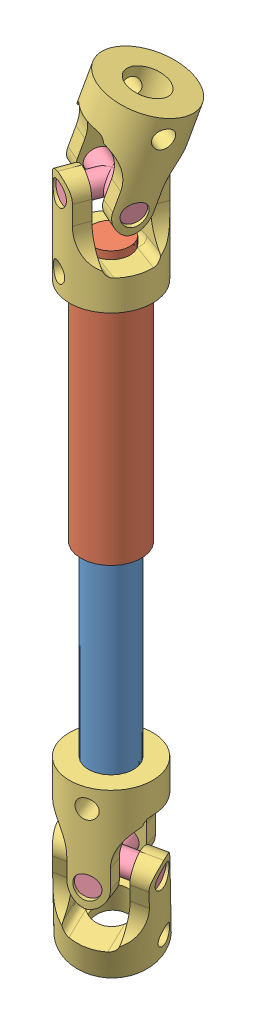
SolidWorks assembly Ujoin axle, configuration Default. Lengths in mm.
Overall size (22.93 105.93 22.35).
10 component instances, 4 part files, 5 mates.
Components (placement in the parent):
- eixo ujoint inner-1: eixo ujoint inner [Default] at (48.7739 -1.5689 21.3495) size (6 45 6)
- eixo ujoint outside-1: eixo ujoint outside [Default] at (48.7739 63.1435 21.3495) x (-0.99996 0 -0.008939) z (-0.008939 0 0.99996) size (8 35 8)
- U-joint-1: U-joint [Default] at (51.0968 80.6209 18.8292) x (-0.979125 0.201993 -0.022648) z (0.022648 0.219152 0.975428) size (16.51 24.62 17) (flexible)
  - u-joint-1: u-joint [Default] x (0.330447 0 0.943825) z (-0.943825 0 0.330447) size (11 14 11)
  - u-joint middle-1: u-joint middle [Default] at (0 11.5 0) x (-0.317657 -0.275522 -0.907294) z (-0.943825 0 0.330447) size (10 2.95 10)
  - u-joint-2: u-joint [Default] at (-2.3229 22.4774 -2.5203) x (0.926441 0.113652 -0.358874) z (-0.317657 -0.275522 -0.907294) size (11 14 11)
- U-joint-2: U-joint [Default] at (46.451 -19.0463 18.8292) x (0.979125 -0.201993 -0.022648) z (-0.022648 -0.219152 0.975428) size (16.51 24.62 17) (flexible)
  - u-joint-1: u-joint [Default] x (0.330447 0 0.943825) z (-0.943825 0 0.330447) size (11 14 11)
  - u-joint middle-1: u-joint middle [Default] at (0 11.5 0) x (-0.317657 -0.275522 -0.907294) z (-0.943825 0 0.330447) size (10 2.95 10)
  - u-joint-2: u-joint [Default] at (-2.3229 22.4774 -2.5203) x (0.926441 0.113652 -0.358874) z (-0.317657 -0.275522 -0.907294) size (11 14 11)
Mates (geometry in assembly coordinates):
- Concentric1: concentric anti-aligned: cylinder of eixo ujoint outside-1 through (48.7739 58.1435 21.3495) axis (0 1 0) radius 2.5; cylinder of U-joint-1/u-joint-2 through (48.7739 62.1435 21.3495) axis (0 -1 0) radius 2.5
- Coincident1: coincident anti-aligned: plane of eixo ujoint outside-1 through (48.7739 58.1435 21.3495) normal (0 1 0); plane of U-joint-1/u-joint-2 through (48.7739 58.1435 21.3495) normal (0 -1 0)
- Concentric2: concentric anti-aligned: cylinder of eixo ujoint inner-1 through (48.7739 43.4311 21.3495) axis (0 -1 0) radius 3; cylinder of eixo ujoint outside-1 through (48.7739 28.1435 21.3495) axis (0 1 0) radius 3
- Concentric3: concentric anti-aligned: cylinder of eixo ujoint inner-1 through (48.7739 3.4311 21.3495) axis (0 -1 0) radius 2.5; cylinder of U-joint-2/u-joint-2 through (48.7739 -0.5689 21.3495) axis (0 1 0) radius 2.5
- Coincident2: coincident anti-aligned: plane of eixo ujoint inner-1 through (48.7739 3.4311 21.3495) normal (0 -1 0); plane of U-joint-2/u-joint-2 through (48.7739 3.4311 21.3495) normal (0 1 0)
